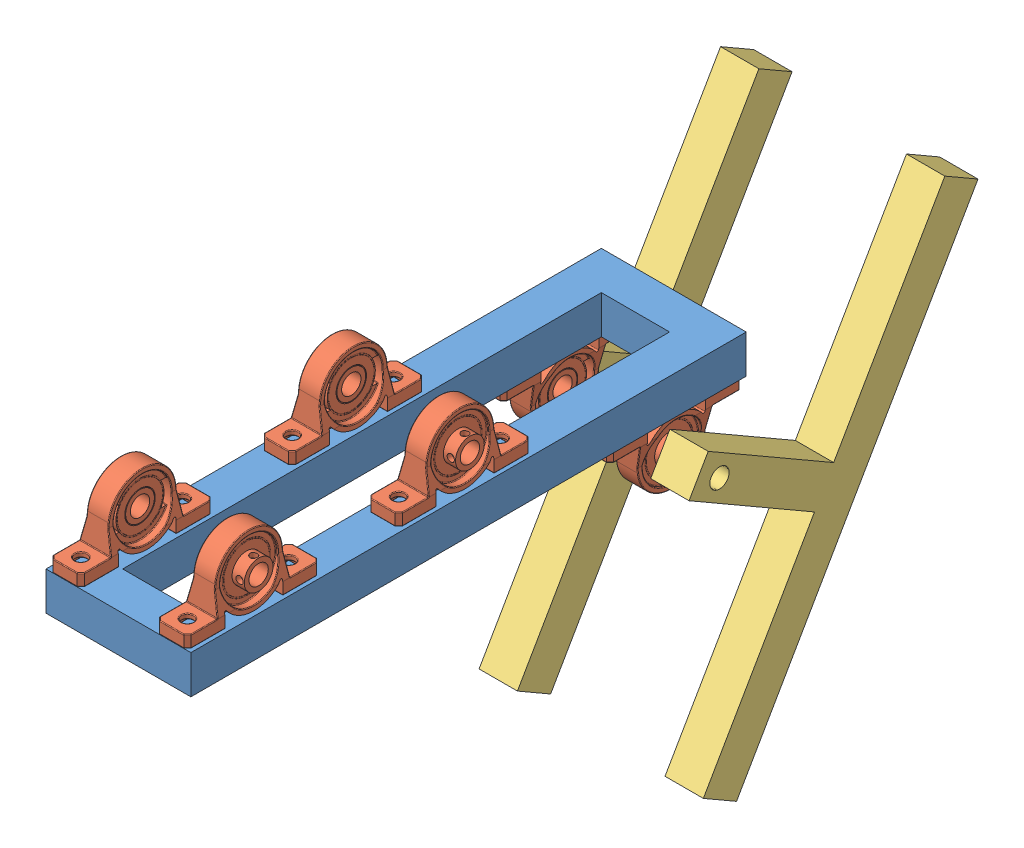
SolidWorks assembly roller_tensioner, configuration Default. Lengths in mm.
Overall size (92.88 211.14 309.55).
9 component instances, 3 part files, 12 mates.
Components (placement in the parent):
- roller_tensioner-1: roller_tensioner [Default] at (-40.6979 7.0705 11.2795) size (60 15.88 230)
- 8mm İç Çap - Rulmanlı Yatak-1: 8mm İç Çap - Rulmanlı Yatak [Varsayılan] at (-62.7604 22.9455 11.2795) x (0 0 -1) z (1 0 0) size (55 28.5 15.02)
- 8mm İç Çap - Rulmanlı Yatak-2: 8mm İç Çap - Rulmanlı Yatak [Varsayılan] at (-18.6354 22.9455 11.2795) x (0 0 1) z (-1 0 0) size (55 28.5 15.02)
- 8mm İç Çap - Rulmanlı Yatak-3: 8mm İç Çap - Rulmanlı Yatak [Varsayılan] at (-62.7604 7.0705 -76.2205) x (0 0 1) z (1 0 0) size (55 28.5 15.02)
- 8mm İç Çap - Rulmanlı Yatak-4: 8mm İç Çap - Rulmanlı Yatak [Varsayılan] at (-18.6354 7.0705 -76.2205) x (0 0 -1) z (-1 0 0) size (55 28.5 15.02)
- roller_pivot-1: roller_pivot [Default] at (-87.1354 -36.3983 -126.3958) x (1 0 0) z (0 -0.866025 0.5) size (15.88 75.88 200)
- roller_pivot-2: roller_pivot [Default] at (5.7396 -36.3983 -126.3958) x (-1 0 0) z (0 0.866025 -0.5) size (15.88 75.88 200)
- 8mm İç Çap - Rulmanlı Yatak-5: 8mm İç Çap - Rulmanlı Yatak [Varsayılan] at (-62.7604 22.9455 98.7795) x (0 0 -1) z (1 0 0) size (55 28.5 15.02)
- 8mm İç Çap - Rulmanlı Yatak-6: 8mm İç Çap - Rulmanlı Yatak [Varsayılan] at (-18.6354 22.9455 98.7795) x (0 0 1) z (-1 0 0) size (55 28.5 15.02)
Mates (geometry in assembly coordinates):
- Coincident1: coincident anti-aligned: plane of roller_tensioner-1 through (-40.6979 22.9455 11.2795) normal (0 1 0); plane of 8mm İç Çap - Rulmanlı Yatak-1 through (-56.2604 22.9455 38.7795) normal (0 -1 0)
- Width1: width anti-aligned: plane of 8mm İç Çap - Rulmanlı Yatak-1 through (-56.2604 27.9455 38.7795) normal (1 0 0); plane of roller_tensioner-1 through (-69.2604 27.9455 38.7795) normal (-1 0 0); plane of 8mm İç Çap - Rulmanlı Yatak-1 through (-70.6979 22.9455 -103.7205) normal (-1 0 0); plane of roller_tensioner-1 through (-54.8229 22.9455 -87.8455) normal (1 0 0)
- Coincident2: coincident aligned: plane of roller_tensioner-1 through (-70.6979 22.9455 -103.7205) normal (0 0 -1); plane of 8mm İç Çap - Rulmanlı Yatak-3 through (-62.7604 7.0705 -103.7205) normal (0 0 -1)
- Coincident3: coincident anti-aligned: plane of roller_tensioner-1 through (-40.6979 7.0705 11.2795) normal (0 -1 0); plane of 8mm İç Çap - Rulmanlı Yatak-3 through (-56.2604 7.0705 -103.7205) normal (0 1 0)
- Width2: width anti-aligned: plane of 8mm İç Çap - Rulmanlı Yatak-3 through (-69.2604 2.0705 -103.7205) normal (-1 0 0); plane of roller_tensioner-1 through (-56.2604 2.0705 -103.7205) normal (1 0 0); plane of 8mm İç Çap - Rulmanlı Yatak-3 through (-54.8229 22.9455 -87.8455) normal (1 0 0); plane of roller_tensioner-1 through (-70.6979 22.9455 -103.7205) normal (-1 0 0)
- Concentric1: concentric aligned: cylinder of 8mm İç Çap - Rulmanlı Yatak-3 through (-71.2604 -7.4295 -76.2205) axis (1 0 0) radius 4; cylinder of roller_pivot-1 through (-87.1354 -7.4295 -76.2205) axis (1 0 0) radius 4
- Coincident4: coincident anti-aligned: plane of 8mm İç Çap - Rulmanlı Yatak-3 through (-71.2604 -7.4295 -76.2205) normal (-1 0 0); plane of roller_pivot-1 through (-71.2604 -36.3983 -126.3958) normal (1 0 0)
- Width3: width anti-aligned: plane of 8mm İç Çap - Rulmanlı Yatak-1 through (-62.7604 22.9455 -16.2205) normal (0 0 -1); plane of roller_tensioner-1 through (-62.7604 22.9455 38.7795) normal (0 0 1); plane of 8mm İç Çap - Rulmanlı Yatak-1 through (-70.6979 22.9455 126.2795) normal (0 0 1); plane of roller_tensioner-1 through (-70.6979 22.9455 -103.7205) normal (0 0 -1)
- Angle1: planar angle = 1.047198 rad anti-aligned: plane of roller_pivot-1 through (-71.2604 -32.4295 -119.5217) normal (0 0.5 0.866025); plane of roller_tensioner-1 through (-40.6979 7.0705 11.2795) normal (0 -1 0)
- Coincident5: coincident anti-aligned: plane of roller_tensioner-1 through (-40.6979 22.9455 11.2795) normal (0 1 0); plane of 8mm İç Çap - Rulmanlı Yatak-5 through (-56.2604 22.9455 126.2795) normal (0 -1 0)
- Width4: width anti-aligned: plane of 8mm İç Çap - Rulmanlı Yatak-5 through (-69.2604 27.9455 126.2795) normal (-1 0 0); plane of roller_tensioner-1 through (-56.2604 27.9455 126.2795) normal (1 0 0); plane of 8mm İç Çap - Rulmanlı Yatak-5 through (-54.8229 22.9455 -87.8455) normal (1 0 0); plane of roller_tensioner-1 through (-70.6979 22.9455 -103.7205) normal (-1 0 0)
- Coincident6: coincident aligned: plane of roller_tensioner-1 through (-70.6979 22.9455 126.2795) normal (0 0 1); plane of 8mm İç Çap - Rulmanlı Yatak-5 through (-62.7604 22.9455 126.2795) normal (0 0 1)
